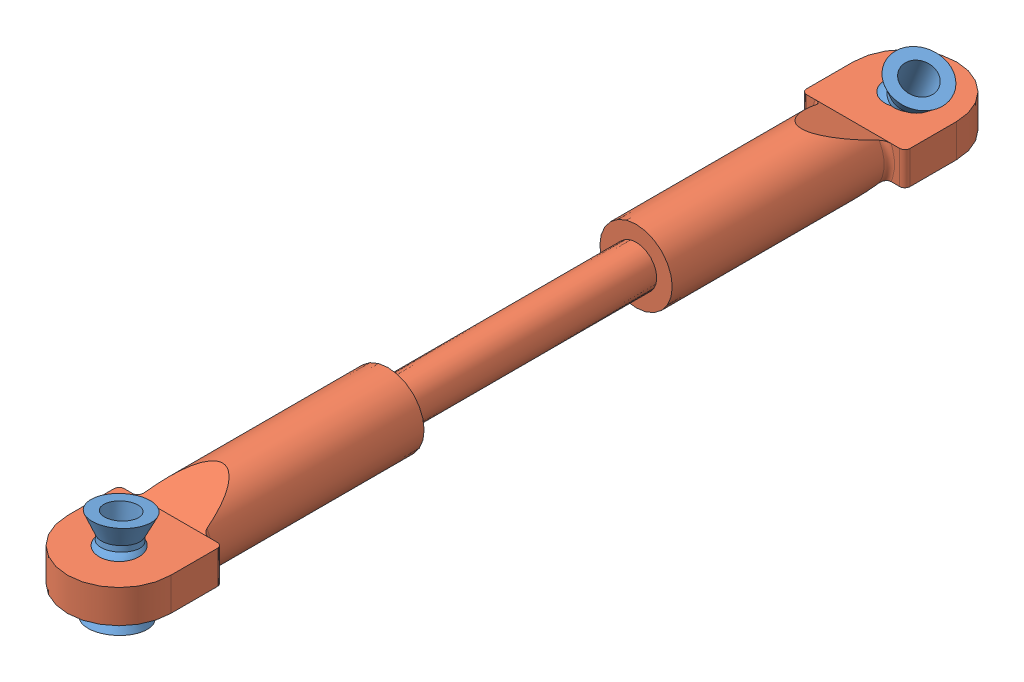
SolidWorks assembly TurnbuckleAssy_fore, configuration Default. Lengths in mm.
Overall size (10 9.69 86).
3 component instances, 2 part files, 2 mates.
Components (placement in the parent):
- Turnbuckle Ball Spacer-1: Turnbuckle Ball Spacer [Default] at (-25.0236 -4.6638 -11.5869) x (0.416171 0.905102 0.087129) z (-0.208661 0.001798 0.977986) size (8.25 5.2 5.2)
- Turnbuckle Bar_fore-1: Turnbuckle Bar_fore [Default] at (-25.0236 -4.6638 26.4131) size (10 7 86)
- Turnbuckle Ball Spacer-2: Turnbuckle Ball Spacer [Default] at (-25.0236 -4.6638 64.4131) x (-0.072069 0.990072 -0.120675) z (-0.090577 0.113993 0.989344) size (8.25 5.2 5.2)
Mates (geometry in assembly coordinates):
- Coincident1: coincident: point of Turnbuckle Ball Spacer-1; point of Turnbuckle Bar_fore-1
- Coincident2: coincident: point of Turnbuckle Bar_fore-1; point of Turnbuckle Ball Spacer-2
